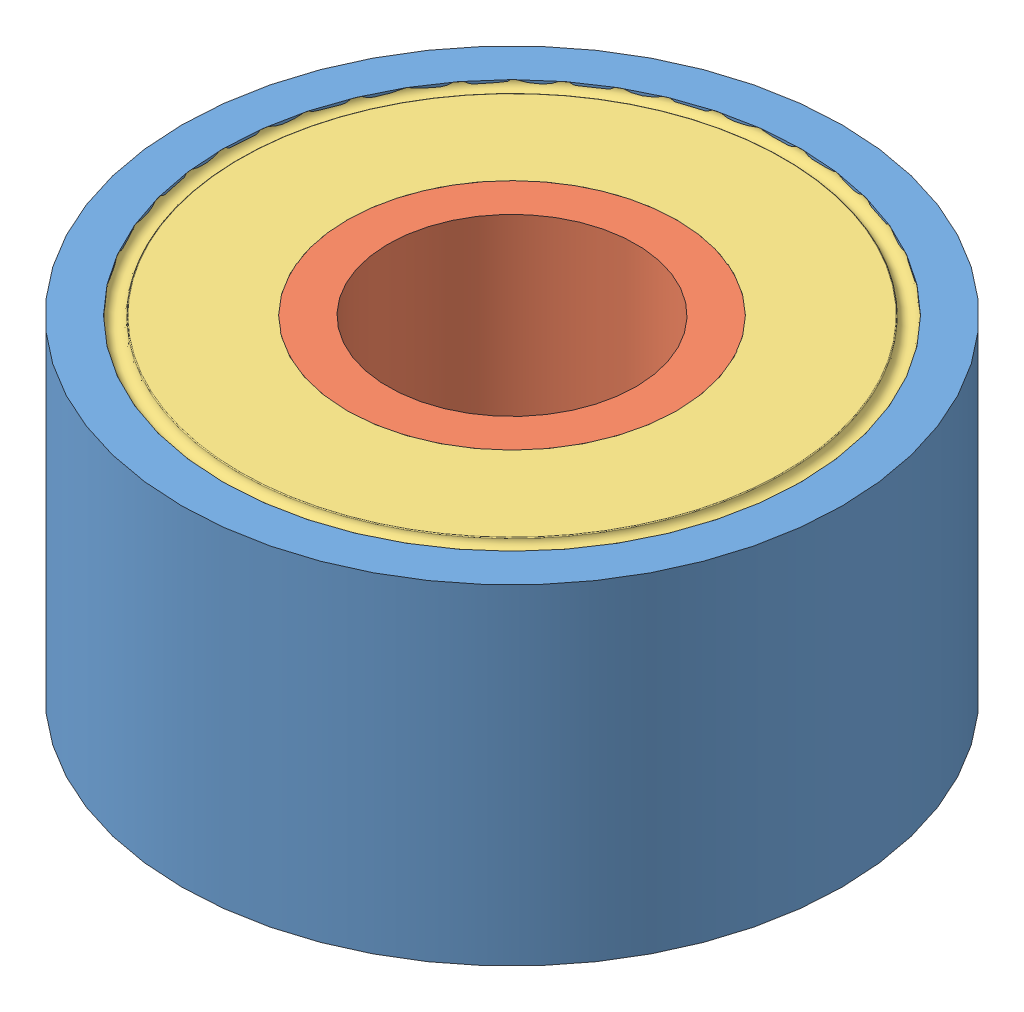
SolidWorks assembly Bearing Subassy, GT2 Idler Pulley, Configurable, configuration 3 mm Bore. Lengths in mm.
Overall size (8 4 8).
10 component instances, 4 part files, 8 mates.
Components (placement in the parent):
- Bearing Outer Ring, GT2 Idler Pulley, Configurable-1: Bearing Outer Ring, GT2 Idler Pulley, Configurable [3 mm Bore] at origin size (8 4 8)
- Bearing Inner Ring, GT2 Idler Pulley, Configurable-1: Bearing Inner Ring, GT2 Idler Pulley, Configurable [3 mm Bore] x (0.926062 0 -0.377371) z (0.377371 0 0.926062) size (4 4 4)
- Bearing Seal, GT2 Idler Pulley, Configurable-1: Bearing Seal, GT2 Idler Pulley, Configurable [3 mm Bore] at (0 1.75 0) size (7 0.5 7)
- Bearing Seal, GT2 Idler Pulley, Configurable-2: Bearing Seal, GT2 Idler Pulley, Configurable [3 mm Bore] at (0 -1.75 0) x (1 0 0) z (0 0 -1) size (7 0.5 7)
- Bearing Ball, GT2 Idler Pulley, Configurable-1: Bearing Ball, GT2 Idler Pulley, Configurable [2 mm] at (1.9442 0 1.9449) x (-0.715461 0 0.698652) z (-0.698652 0 -0.715461) size (2 2 2)
- Bearing Ball, GT2 Idler Pulley, Configurable-2: Bearing Ball, GT2 Idler Pulley, Configurable [2 mm] at (-0.7122 0 2.6562) x (-0.962781 0 -0.270282) z (0.270282 0 -0.962781) size (2 2 2)
- Bearing Ball, GT2 Idler Pulley, Configurable-3: Bearing Ball, GT2 Idler Pulley, Configurable [2 mm] at (-2.6564 0 0.7113) x (-0.24732 0 -0.968934) z (0.968934 0 -0.24732) size (2 2 2)
- Bearing Ball, GT2 Idler Pulley, Configurable-4: Bearing Ball, GT2 Idler Pulley, Configurable [2 mm] at (-1.9442 0 -1.9449) x (0.715461 0 -0.698652) z (0.698652 0 0.715461) size (2 2 2)
- Bearing Ball, GT2 Idler Pulley, Configurable-5: Bearing Ball, GT2 Idler Pulley, Configurable [2 mm] at (0.7122 0 -2.6562) x (0.962781 0 0.270282) z (-0.270282 0 0.962781) size (2 2 2)
- Bearing Ball, GT2 Idler Pulley, Configurable-6: Bearing Ball, GT2 Idler Pulley, Configurable [2 mm] at (2.6564 0 -0.7113) x (0.24732 0 0.968934) z (-0.968934 0 0.24732) size (2 2 2)
Mates (geometry in assembly coordinates):
- Coincident1: coordinate: point of Bearing Outer Ring, GT2 Idler Pulley, Configurable-1
- Concentric1: concentric aligned: cylinder of Bearing Outer Ring, GT2 Idler Pulley, Configurable-1 through (0 2 0) axis (0 -1 0) radius 3.5; cylinder of Bearing Inner Ring, GT2 Idler Pulley, Configurable-1 through (0 2 0) axis (0 -1 0) radius 1.5
- Coincident2: coincident aligned: plane of Bearing Inner Ring, GT2 Idler Pulley, Configurable-1 through (0 0 0) normal (0 1 0)
- Concentric2: concentric aligned: cylinder of Bearing Outer Ring, GT2 Idler Pulley, Configurable-1 through (0 2 0) axis (0 -1 0) radius 3.5; cylinder of Bearing Seal, GT2 Idler Pulley, Configurable-1 through (0 2 0) axis (0 -1 0) radius 3.5
- Coincident3: coincident aligned: plane of Bearing Outer Ring, GT2 Idler Pulley, Configurable-1 through (0 2 0) normal (0 1 0); plane of Bearing Seal, GT2 Idler Pulley, Configurable-1 through (0 2 0) normal (0 1 0)
- Coincident4: coincident aligned: plane of Bearing Seal, GT2 Idler Pulley, Configurable-1 through (0 1.75 0) normal (1 0 0)
- Tangent1: tangent: torus of assembly; sphere of assembly; torus of Bearing Outer Ring, GT2 Idler Pulley, Configurable-1; sphere of Bearing Ball, GT2 Idler Pulley, Configurable-1
- Coincident5: coincident aligned: plane of Bearing Ball, GT2 Idler Pulley, Configurable-1 through (1.9442 0 1.9449) normal (0 1 0)
